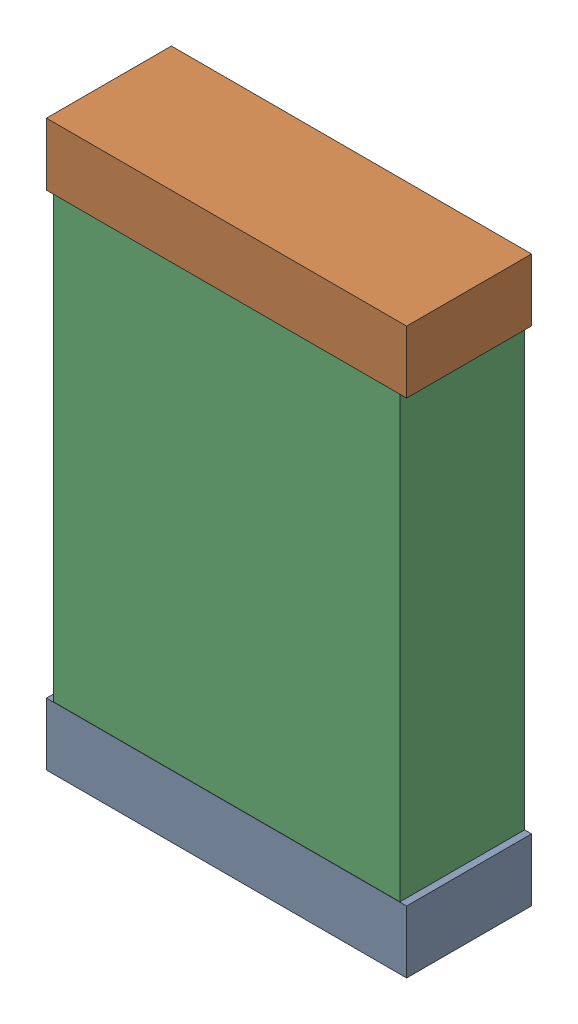
SolidWorks assembly C47, configuration Default. Lengths in mm.
Overall size (1.3 2.04 0.45).
6 component instances, 2 part files, 0 mates.
Components (placement in the parent):
- 740902240-1: 740902240 [Default] at (72.8972 21.3736 0) size (1.3 0.23 0.45)
  - Extruded_35-1: Extruded_35 [Default] at origin size (1.3 0.23 0.45)
- 740902240-2: 740902240 [Default] at (72.8972 23.1861 0) size (1.3 0.23 0.45)
  - Extruded_35-1: Extruded_35 [Default] at origin size (1.3 0.23 0.45)
- 740904480-1: 740904480 [Default] at (72.8972 22.2736 0) size (1.25 2 0.45)
  - Extruded_34-1: Extruded_34 [Default] at origin size (1.25 2 0.45)
